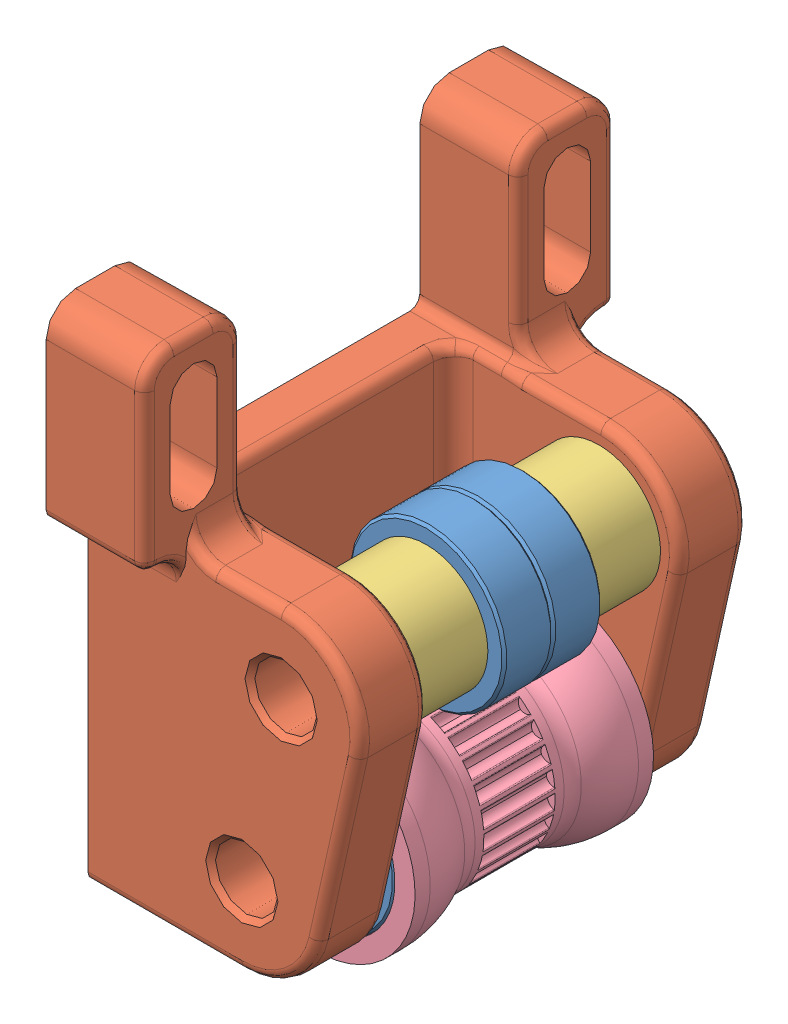
SolidWorks assembly teststand_base_belt_tensioner, configuration Default. Lengths in mm.
Overall size (30.4 55 48).
8 component instances, 4 part files, 17 mates.
Components (placement in the parent):
- 60355K430_BALL BEARING-1: 60355K430_BALL BEARING [60355K43] at (15.65 8 10.1358) x (0 -1 0) z (0 0 1) size (15.88 15.88 4.98)
- testrig slot belttensionholder-1: testrig slot belttensionholder [Default] at (15.65 8 19.75) x (0 -1 0) z (0 0 1) size (53.19 30.4 48)
- teststand_spacer-1: teststand_spacer [Default] at (19.65 26 7.1716) x (1 0 0) z (0 -1 0) size (12.5 7.6 12.5)
- teststand_tensioner_pulley_clamp-1: teststand_tensioner_pulley_clamp [bigger] at (4.8789 12.3718 5.3451) x (0 -1 0) z (0 0 1) size (20 20 24.25)
- 60355K430_BALL BEARING-2: 60355K430_BALL BEARING [60355K43] at (15.65 8 29.3642) x (0 -1 0) z (0 0 1) size (15.88 15.88 4.98)
- 60355K430_BALL BEARING-5: 60355K430_BALL BEARING [60355K43] at (19.65 26 22.2392) x (0 -1 0) z (0 0 1) size (15.88 15.88 4.98)
- 60355K430_BALL BEARING-6: 60355K430_BALL BEARING [60355K43] at (19.65 26 17.2608) x (0 -1 0) z (0 0 1) size (15.88 15.88 4.98)
- teststand_spacer-2: teststand_spacer [Default] at (19.65 26 24.7284) x (1 0 0) z (0 -1 0) size (12.5 7.6 12.5)
Mates (geometry in assembly coordinates):
- Concentric4: concentric: cylinder of 60355K430_BALL BEARING-1 through (15.65 8 12.625) axis (0 0 1) radius 7.9375; cylinder of teststand_tensioner_pulley_clamp-1 through (15.65 8 7.625) axis (0 0 1) radius 7.95
- Coincident3: coincident: plane of 60355K430_BALL BEARING-1 through (23.3386 8 12.625) normal (0 0 1); plane of teststand_tensioner_pulley_clamp-1 through (15.65 8 12.625) normal (0 0 -1)
- Concentric5: concentric: cylinder of teststand_tensioner_pulley_clamp-1 through (15.65 8 31.875) axis (0 0 -1) radius 7.95; cylinder of 60355K430_BALL BEARING-2 through (15.65 8 31.8534) axis (0 0 1) radius 7.9375
- Coincident4: coincident: plane of teststand_tensioner_pulley_clamp-1 through (15.65 8 26.875) normal (0 0 1); plane of 60355K430_BALL BEARING-2 through (23.3386 8 26.875) normal (0 0 -1)
- Width1: width: plane of testrig slot belttensionholder-1 through (15.65 8 32.5) normal (0 0 -1); plane of testrig slot belttensionholder-1 through (15.65 8 7) normal (0 0 1); plane of 60355K430_BALL BEARING-1 through (19.0739 8 7.6466) normal (0 0 -1); plane of 60355K430_BALL BEARING-2 through (20.7273 8 31.8534) normal (0 0 1)
- Concentric10: concentric: cylinder of testrig slot belttensionholder-1 through (15.65 8 39.5) axis (0 0 -1) radius 3.175; cylinder of 60355K430_BALL BEARING-2 through (15.65 8 31.8534) axis (0 0 1) radius 3.175
- Concentric12: concentric: cylinder of 60355K430_BALL BEARING-5 through (19.65 26 24.7284) axis (0 0 1) radius 3.175; cylinder of 60355K430_BALL BEARING-6 through (19.65 26 19.75) axis (0 0 1) radius 3.175
- Coincident9: coincident: plane of 60355K430_BALL BEARING-5 through (23.0739 26 19.75) normal (0 0 -1); plane of 60355K430_BALL BEARING-6 through (24.7273 26 19.75) normal (0 0 1)
- Concentric13: concentric: cylinder of teststand_spacer-1 through (19.65 26 14.7716) axis (0 0 -1) radius 3.25; cylinder of 60355K430_BALL BEARING-6 through (19.65 26 19.75) axis (0 0 1) radius 3.175
- Coincident10: coincident: plane of teststand_spacer-1 through (19.65 26 14.7716) normal (0 0 1); plane of 60355K430_BALL BEARING-6 through (23.0739 26 14.7716) normal (0 0 -1)
- Coincident11: coincident: plane of 60355K430_BALL BEARING-5 through (24.7273 26 24.7284) normal (0 0 1); plane of teststand_spacer-2 through (19.65 26 24.7284) normal (0 0 -1)
- Concentric14: concentric: cylinder of 60355K430_BALL BEARING-5 through (19.65 26 24.7284) axis (0 0 1) radius 3.175; cylinder of teststand_spacer-2 through (19.65 26 32.3284) axis (0 0 -1) radius 3.25
- Concentric15: concentric: cylinder of testrig slot belttensionholder-1 through (19.65 26 0) axis (0 0 1) radius 3.175; cylinder of teststand_spacer-2 through (19.65 26 32.3284) axis (0 0 -1) radius 3.25
- Width2: width: plane of testrig slot belttensionholder-1 through (15.65 8 7) normal (0 0 1); plane of testrig slot belttensionholder-1 through (15.65 8 32.5) normal (0 0 -1); plane of teststand_spacer-2 through (19.65 26 32.3284) normal (0 0 1); plane of teststand_spacer-1 through (19.65 26 7.1716) normal (0 0 -1)
- Coincident12: coincident: plane of testrig slot belttensionholder-1 through (0 8 19.75) normal (-1 0 0); plane of assembly through (0 0 0) normal (1 0 0)
- Coincident13: coincident: plane of testrig slot belttensionholder-1 through (4.65 0 39.5) normal (0 -1 0); plane of assembly through (0 0 0) normal (0 1 0)
- Coincident14: coincident: plane of testrig slot belttensionholder-1 through (0 34 0) normal (0 0 -1); plane of assembly through (0 0 0) normal (0 0 1)
